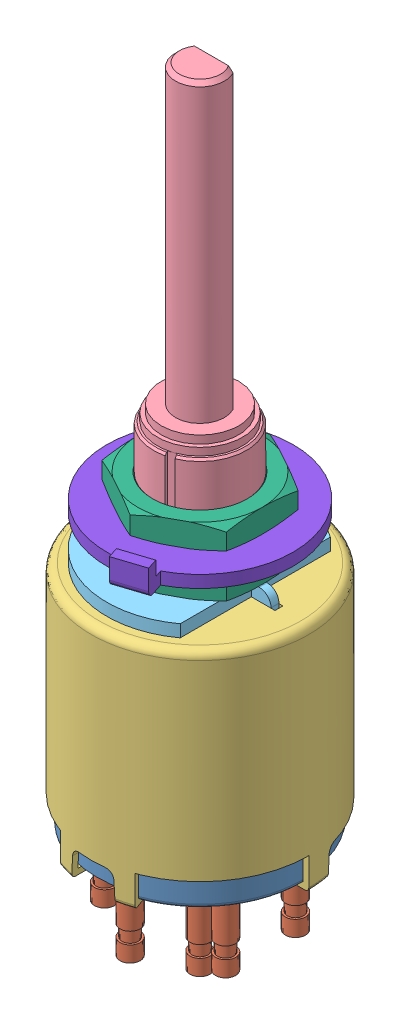
SolidWorks assembly MRY106_NKK_Switch, Rotary, 2-6 POS, configuration Default. Lengths in mm.
Overall size (15.45 46.47 16.17).
9 component instances, 8 part files, 0 mates.
Components (placement in the parent):
- _MRYbodyp-1: _MRYbodyp [Default] at origin size (13.23 14.22 13.23)
- _MRY106ptrmnls-1: _MRY106ptrmnls [Default] at (0 0.0762 0) size (10.69 8.1 10.69)
- _MRYpp-1: _MRYpp [Default] at origin size (14 14.88 14)
- _MRYpshaft-1: _MRYpshaft [Copy of Default] at (0 14.605 0) size (6.25 23.86 6.25)
- _MRYhardp-1: _MRYhardp [Default] at (0 14.605 0) x (0.99863 0 -0.052336) z (0.052336 0 0.99863) size (10.83 2.06 11.99)
- _AT513M-1: _AT513M [Default] at (0 16.1417 0) x (0 0 1) z (0 1 0) size (8.99 8 1.5)
- _AT513M-2: _AT513M [Default] at (0 18.9357 0) x (0 0 1) z (0 1 0) size (8.99 8 1.5)
- _AT509-1: _AT509 [Default] at (0 17.145 0) x (1 0 0) z (0 1 0) size (10.21 10.21 0.51)
- _AT507M-1: _AT507M [Default] at (0 17.399 0) x (-0.309017 0 -0.951057) z (0 1 0) size (13.11 11.99 1.7)
